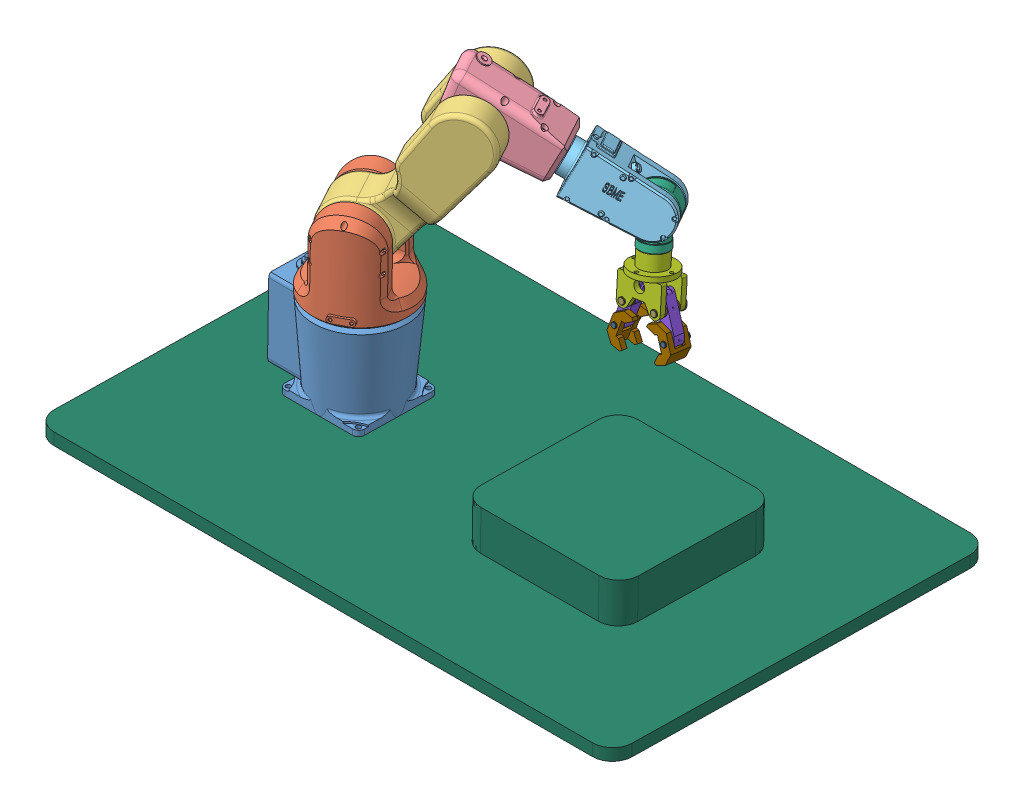
SolidWorks assembly ROBOT, configuration 默认. Lengths in mm.
Overall size (1469.52 833.22 964.73).
25 component instances, 15 part files, 14 mates.
Components (placement in the parent):
- 0-1: 0 [默认] at (0 72.9247 -71.4969) x (1 0 0) z (0 0.017452 0.999848) size (299.76 239.19 271.11)
- 1_1-1: 1_1 [默认] at (0 293.8911 -75.3539) x (-0.48308 -0.015281 -0.875443) z (0.875576 -0.008431 -0.483007) size (332.05 234.42 332.05)
- 2-1: 2 [默认] at (188.7687 725.7234 -187.0564) x (-0.697288 0.611424 0.374099) z (0.52955 0.791155 -0.306022) size (161.49 235.01 500.53)
- 3_1-1: 3_1 [默认] at (330.9729 670.3039 -264.5591) x (-0.792766 0.43208 0.429916) z (-0.371692 -0.901706 0.220844) size (250.17 103 166.59)
- 4-1: 4 [默认] at (481.9261 588.0301 -346.4208) x (0.792766 -0.43208 -0.429916) z (0.551233 0.207223 0.808208) size (240.42 124.25 113.23)
- 5_1-1: 5_1 [默认] at (481.9261 588.0301 -346.4208) x (0.827303 -0.010105 -0.561665) z (-0.551233 -0.207223 -0.808208) size (124.75 145.38 68)
- joint7-1: joint7 [默认] at (490.5839 509.7708 -332.2603) x (-0.053732 -0.183548 -0.981541) z (-0.108223 0.978241 -0.177007) size (105 164.84 211.36)
  - 14-1: 14 [默认] at origin size (105 105 121)
  - 18-1: 18 [默认] at (0 38.5 -107) x (0 0.344424 -0.938814) z (1 0 0) size (109.57 29 28)
  - 19-1: 19 [默认] at (0 69.5489 -159.698) x (0 0.330078 -0.943954) z (1 0 0) size (78 45 56)
  - 22-1: 22 [默认] at (35 59.1654 -163.3289) x (0 -0.811761 -0.583989) z (-1 0 0) size (18 18 66)
  - 24-1: 24 [默认] at (-21 38.5 -107) x (0 -0.533782 -0.845622) z (1 0 0) size (26 26 7)
  - 25-1: 25 [默认] at (44 38.5 -107) x (-1 0 0) z (0 -0.659078 -0.752075) size (82 21 21)
  - 24-2: 24 [默认] at (21 38.5 -107) x (0 -0.699829 -0.71431) z (-1 0 0) size (26 26 7)
  - 26-1: 26 [默认] at (26.3555 38.5 -107) x (0 -0.33616 0.941805) z (0 0.941805 0.33616) size (30 3 30)
  - 23-1: 23 [默认] at (28 59.1654 -163.3289) x (0 -0.043815 -0.99904) z (1 0 0) size (20 20 3)
  - 19-2: 19 [默认] at (0 -69.5489 -159.698) x (0 -0.330078 -0.943954) z (-1 0 0) size (78 45 56)
  - 18-2: 18 [默认] at (0 -38.5 -107) x (0 -0.344424 -0.938814) z (-1 0 0) size (109.57 29 28)
  - 22-2: 22 [默认] at (35 -59.1654 -163.3289) x (0 -0.811761 0.583989) z (-1 0 0) size (18 18 66)
  - 23-2: 23 [默认] at (31 -59.1654 -163.3289) x (0 0.043815 -0.99904) z (-1 0 0) size (20 20 3)
  - 25-2: 25 [默认] at (44 -38.5 -107) x (-1 0 0) z (0 -0.659078 0.752075) size (82 21 21)
  - 26-2: 26 [默认] at (26.3555 -38.5 -107) x (0 0.33616 0.941805) z (0 0.941805 -0.33616) size (30 3 30)
  - 24-3: 24 [默认] at (14 -38.5 -107) x (0 0.699829 -0.71431) z (1 0 0) size (26 26 7)
  - 24-4: 24 [默认] at (-14 -38.5 -107) x (0 0.533782 -0.845622) z (-1 0 0) size (26 26 7)
- 零件3-1: 零件3 [默认] at (0 72.9247 -71.4969) x (-1 0 0) z (0 -0.999848 0.017452) size (1469.52 959.99 280)
Mates (geometry in assembly coordinates):
- 重合1: coincident: plane of 0-1 through (0 291.8914 -75.319) normal (0 0.999848 -0.017452); plane of 1_1-1 through (0 291.8914 -75.319) normal (0 -0.999848 0.017452)
- 重合2: coincident: plane of 0-1 through (0 291.8914 -75.319) normal (0 0.999848 -0.017452); plane of 1_1-1 through (0 291.8914 -75.319) normal (0 -0.999848 0.017452)
- 同心1: concentric: circle of 0-1; circle of 1_1-1
- 重合3: coincident: plane of 1_1-1 through (0 293.8911 -75.3539) normal (-0.48308 -0.015281 -0.875443); plane of 2-1 through (188.7687 725.7234 -187.0564) normal (0.48308 0.015281 0.875443)
- 同心2: concentric: circle of 1_1-1; circle of 2-1
- 重合4: coincident: plane of 2-1 through (188.7687 725.7234 -187.0564) normal (0.48308 0.015281 0.875443); plane of 3_1-1 through (330.9729 670.3039 -264.5591) normal (-0.48308 -0.015281 -0.875443)
- 同心3: concentric: circle of 2-1; circle of 3_1-1
- 同心4: concentric: circle of 3_1-1; cylinder of 4-1 through (330.9729 670.3039 -264.5591) axis (0.792766 -0.43208 -0.429916) radius 39.035
- 重合6: coincident: plane of 3_1-1 through (288.2343 624.4545 -297.289) normal (0.792766 -0.43208 -0.429916); plane of 4-1 through (330.9729 670.3039 -264.5591) normal (-0.792766 0.43208 0.429916)
- 重合7: coincident: plane of 4-1 through (481.9261 588.0301 -346.4208) normal (0.551233 0.207223 0.808208); plane of 5_1-1 through (481.9261 588.0301 -346.4208) normal (-0.551233 -0.207223 -0.808208)
- 同心5: concentric: circle of 4-1; circle of 5_1-1
- 同心6: concentric: cylinder of 5_1-1 through (488.4195 529.3356 -335.8004) axis (0.108223 -0.978241 0.177007) radius 34; cylinder of joint7-1/14-1 through (490.5839 509.7708 -332.2603) axis (0.108223 -0.978241 0.177007) radius 26
- 重合8: coincident: plane of 5_1-1 through (490.5839 509.7708 -332.2603) normal (0.108223 -0.978241 0.177007); plane of joint7-1/14-1 through (490.5839 509.7708 -332.2603) normal (-0.108223 0.978241 -0.177007)
- 路径配合1: path: point of joint7-1/14-1; circle of 零件3-1
